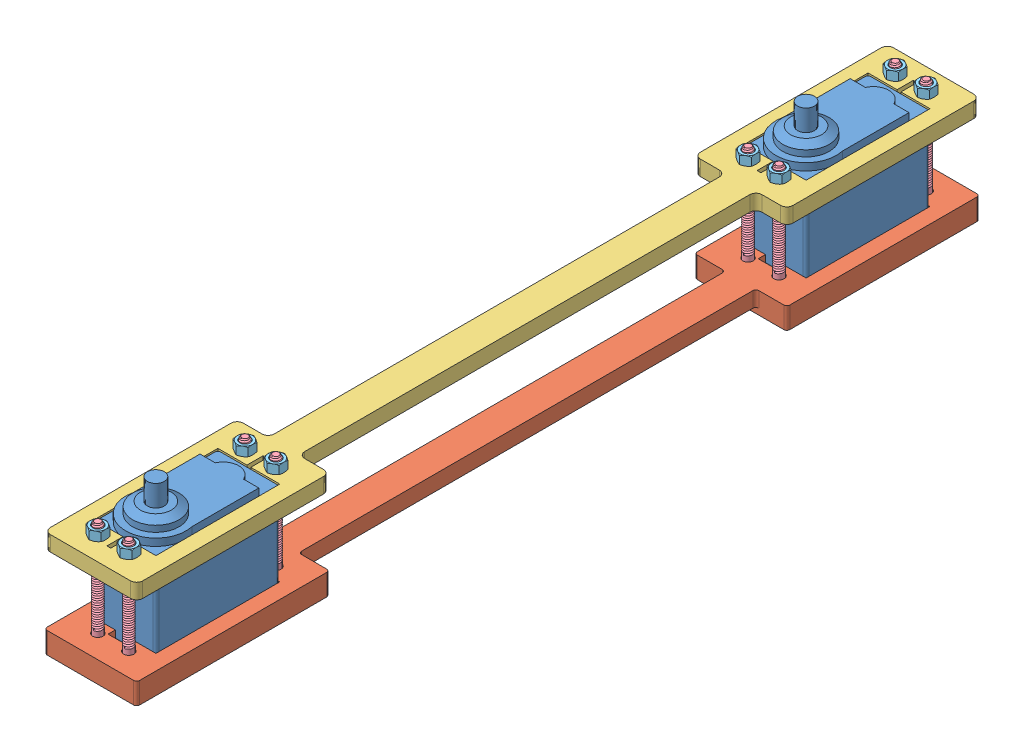
SolidWorks assembly Assem4, configuration Default. Lengths in mm.
Overall size (30.32 57.1 276.6).
20 component instances, 5 part files, 49 mates.
Components (placement in the parent):
- Motor3-1: Motor3 [Default] at origin size (20.32 45.1 53.29)
- Motor3-2: Motor3 [Default] at (0 0 -213.3) size (20.32 45.1 53.29)
- Part3-1: Part3 [Default] at (0 -35.6 -223.4854) x (0 -1 0) z (0 0 -1) size (17 30.32 276.6)
- Part4-1: Part4 [Default] at (0 -12.82 -10.1854) x (0 1 0) z (0 0 1) size (5 30.32 276.6)
- straf3_dolg37-1: straf3_dolg37 [Default] at (5.08 -40.74 13.9446) x (1 0 0) z (0 0 -1) size (7.72 39.83 7.72)
- straf3_dolg37-2: straf3_dolg37 [Default] at (-5.08 -40.74 13.9446) x (1 0 0) z (0 0 -1) size (7.72 39.83 7.72)
- straf3_dolg37-3: straf3_dolg37 [Default] at (-5.08 -40.74 -34.3154) x (1 0 0) z (0 0 -1) size (7.72 39.83 7.72)
- straf3_dolg37-4: straf3_dolg37 [Default] at (5.08 -40.74 -34.3154) x (1 0 0) z (0 0 -1) size (7.72 39.83 7.72)
- straf3_dolg37-6: straf3_dolg37 [Default] at (5.08 -40.74 -199.3554) x (1 0 0) z (0 0 -1) size (7.72 39.83 7.72)
- straf3_dolg37-5: straf3_dolg37 [Default] at (-5.08 -40.74 -199.3554) x (1 0 0) z (0 0 -1) size (7.72 39.83 7.72)
- straf3_dolg37-7: straf3_dolg37 [Default] at (-5.08 -40.74 -247.6154) x (1 0 0) z (0 0 -1) size (7.72 39.83 7.72)
- straf3_dolg37-8: straf3_dolg37 [Default] at (5.08 -40.74 -247.6154) x (0 0 1) z (1 0 0) size (7.72 39.83 7.72)
- navrtka2-1: navrtka2 [Default] at (-5.08 -6.32 13.9446) x (0.998982 0 -0.0451) z (0 -1 0) size (5.57 5.77 3)
- navrtka2-2: navrtka2 [Default] at (5.08 -6.32 13.9446) x (0.998982 0 -0.0451) z (0 -1 0) size (5.57 5.77 3)
- navrtka2-3: navrtka2 [Default] at (-5.08 -6.32 -34.3154) x (0.998982 0 -0.0451) z (0 -1 0) size (5.57 5.77 3)
- navrtka2-4: navrtka2 [Default] at (5.08 -6.32 -34.3154) x (0.998982 0 -0.0451) z (0 -1 0) size (5.57 5.77 3)
- navrtka2-5: navrtka2 [Default] at (-5.08 -6.32 -199.3554) x (0.998982 0 -0.0451) z (0 -1 0) size (5.57 5.77 3)
- navrtka2-6: navrtka2 [Default] at (-5.08 -6.32 -247.6154) x (0.998982 0 -0.0451) z (0 -1 0) size (5.57 5.77 3)
- navrtka2-7: navrtka2 [Default] at (5.08 -6.32 -247.6154) x (0.998982 0 -0.0451) z (0 -1 0) size (5.57 5.77 3)
- navrtka2-8: navrtka2 [Default] at (5.08 -6.32 -199.3554) x (0.998982 0 -0.0451) z (0 -1 0) size (5.57 5.77 3)
Mates (geometry in assembly coordinates):
- Concentric1: concentric aligned: cylinder of Motor3-1 through (5.08 -12.82 13.9446) axis (0 -1 0) radius 1.5; cylinder of Part4-1 through (5.08 -7.82 13.9446) axis (0 -1 0) radius 1.5
- Concentric2: concentric aligned: cylinder of Motor3-1 through (-5.08 -12.82 -34.3154) axis (0 -1 0) radius 1.5; cylinder of Part4-1 through (-5.08 -7.82 -34.3154) axis (0 -1 0) radius 1.5
- Coincident7: coincident anti-aligned: plane of Motor3-1 through (0 -12.82 -20.3454) normal (0 1 0); plane of Part4-1 through (0 -12.82 -10.1854) normal (0 -1 0)
- Concentric3: concentric aligned: cylinder of Part3-1 through (5.08 -42.6 13.9446) axis (0 -1 0) radius 1.7; cylinder of Part4-1 through (5.08 -7.82 13.9446) axis (0 -1 0) radius 1.5
- Concentric4: concentric aligned: cylinder of Part3-1 through (-5.08 -42.6 -247.6154) axis (0 -1 0) radius 1.7; cylinder of Part4-1 through (-5.08 -7.82 -247.6154) axis (0 -1 0) radius 1.5
- Concentric5: concentric aligned: cylinder of Motor3-2 through (-5.08 -12.82 -247.6154) axis (0 -1 0) radius 1.5; cylinder of Part4-1 through (-5.08 -7.82 -247.6154) axis (0 -1 0) radius 1.5
- Concentric6: concentric aligned: cylinder of Motor3-2 through (5.08 -12.82 -199.3554) axis (0 -1 0) radius 1.5; cylinder of Part4-1 through (5.08 -7.82 -199.3554) axis (0 -1 0) radius 1.5
- Coincident8: coincident anti-aligned: plane of Motor3-2 through (0 -12.82 -233.6454) normal (0 1 0); plane of Part4-1 through (0 -12.82 -10.1854) normal (0 -1 0)
- Coincident9: coincident anti-aligned: plane of Motor3-2 through (0 -40.6 -233.6454) normal (0 -1 0); plane of Part3-1 through (0 -40.6 -223.4854) normal (0 1 0)
- Coincident10: coincident aligned: cone of Part3-1 through (5.08 -42.6 -247.6154) axis (0 1 0); cone of straf3_dolg37-8 through (5.08 -40.74 -247.6154) axis (0 1 0)
- Coincident11: coincident aligned: cone of Part3-1 through (-5.08 -42.6 -247.6154) axis (0 1 0); cone of straf3_dolg37-7 through (-5.08 -40.74 -247.6154) axis (0 1 0)
- Coincident12: coincident aligned: cone of Part3-1 through (5.08 -42.6 -199.3554) axis (0 1 0); cone of straf3_dolg37-6 through (5.08 -40.74 -199.3554) axis (0 1 0)
- Coincident13: coincident aligned: cone of Part3-1 through (-5.08 -42.6 -199.3554) axis (0 1 0); cone of straf3_dolg37-5 through (-5.08 -40.74 -199.3554) axis (0 1 0)
- Coincident14: coincident aligned: cone of Part3-1 through (5.08 -42.6 -34.3154) axis (0 1 0); cone of straf3_dolg37-4 through (5.08 -40.74 -34.3154) axis (0 1 0)
- Coincident15: coincident aligned: cone of Part3-1 through (-5.08 -42.6 -34.3154) axis (0 1 0); cone of straf3_dolg37-3 through (-5.08 -40.74 -34.3154) axis (0 1 0)
- Coincident16: coincident aligned: cone of Part3-1 through (5.08 -42.6 13.9446) axis (0 1 0); cone of straf3_dolg37-1 through (5.08 -40.74 13.9446) axis (0 1 0)
- Coincident17: coincident aligned: cone of Part3-1 through (-5.08 -42.6 13.9446) axis (0 1 0); cone of straf3_dolg37-2 through (-5.08 -40.74 13.9446) axis (0 1 0)
- Concentric15: concentric anti-aligned: cylinder of Part4-1 through (5.08 -7.82 -247.6154) axis (0 -1 0) radius 1.5; circle of navrtka2-7
- Coincident18: coincident anti-aligned: plane of Part4-1 through (0 -7.82 -10.1854) normal (0 1 0); plane of navrtka2-7 through (5.08 -7.82 -247.6154) normal (0 -1 0)
- Concentric16: concentric anti-aligned: cylinder of Part4-1 through (-5.08 -7.82 -247.6154) axis (0 -1 0) radius 1.5; circle of navrtka2-6
- Coincident19: coincident anti-aligned: plane of Part4-1 through (0 -7.82 -10.1854) normal (0 1 0); plane of navrtka2-6 through (-5.08 -7.82 -247.6154) normal (0 -1 0)
- Concentric17: concentric anti-aligned: cylinder of Part4-1 through (5.08 -7.82 -199.3554) axis (0 -1 0) radius 1.5; circle of navrtka2-8
- Coincident20: coincident anti-aligned: plane of Part4-1 through (0 -7.82 -10.1854) normal (0 1 0); plane of navrtka2-8 through (5.08 -7.82 -199.3554) normal (0 -1 0)
- Concentric18: concentric anti-aligned: cylinder of Part4-1 through (-5.08 -7.82 -199.3554) axis (0 -1 0) radius 1.5; circle of navrtka2-5
- Coincident21: coincident anti-aligned: plane of Part4-1 through (0 -7.82 -10.1854) normal (0 1 0); plane of navrtka2-5 through (-5.08 -7.82 -199.3554) normal (0 -1 0)
- Concentric19: concentric anti-aligned: cylinder of Part4-1 through (5.08 -7.82 -34.3154) axis (0 -1 0) radius 1.5; circle of navrtka2-4
- Coincident22: coincident anti-aligned: plane of Part4-1 through (0 -7.82 -10.1854) normal (0 1 0); plane of navrtka2-4 through (5.08 -7.82 -34.3154) normal (0 -1 0)
- Concentric20: concentric anti-aligned: cylinder of Part4-1 through (-5.08 -7.82 -34.3154) axis (0 -1 0) radius 1.5; circle of navrtka2-3
- Coincident23: coincident anti-aligned: plane of Part4-1 through (0 -7.82 -10.1854) normal (0 1 0); plane of navrtka2-3 through (-5.08 -7.82 -34.3154) normal (0 -1 0)
- Concentric21: concentric anti-aligned: cylinder of Part4-1 through (5.08 -7.82 13.9446) axis (0 -1 0) radius 1.5; circle of navrtka2-2
- Coincident24: coincident anti-aligned: plane of Part4-1 through (0 -7.82 -10.1854) normal (0 1 0); plane of navrtka2-2 through (5.08 -7.82 13.9446) normal (0 -1 0)
- Concentric22: concentric anti-aligned: cylinder of Part4-1 through (-5.08 -7.82 13.9446) axis (0 -1 0) radius 1.5; circle of navrtka2-1
- Coincident25: coincident anti-aligned: plane of Part4-1 through (0 -7.82 -10.1854) normal (0 1 0); plane of navrtka2-1 through (-5.08 -7.82 13.9446) normal (0 -1 0)
- Parallel1: parallel aligned: plane of Part4-1 through (15.16 -7.82 -10.1854) normal (1 0 0); plane of navrtka2-2 through (7.58 -4.82 12.5012) normal (1 0 0)
- Parallel2: parallel aligned: plane of Part4-1 through (15.16 -7.82 -10.1854) normal (1 0 0); plane of navrtka2-1 through (-2.58 -4.82 12.5012) normal (1 0 0)
- Parallel3: parallel aligned: plane of Part4-1 through (15.16 -7.82 -10.1854) normal (1 0 0); plane of navrtka2-3 through (-2.58 -4.82 -35.7588) normal (1 0 0)
- Parallel4: parallel aligned: plane of Part4-1 through (15.16 -7.82 -10.1854) normal (1 0 0); plane of navrtka2-4 through (7.58 -4.82 -35.7588) normal (1 0 0)
- Parallel5: parallel aligned: plane of Part4-1 through (15.16 -7.82 -10.1854) normal (1 0 0); plane of navrtka2-8 through (7.58 -4.82 -200.7988) normal (1 0 0)
- Parallel6: parallel aligned: plane of Part4-1 through (15.16 -7.82 -10.1854) normal (1 0 0); plane of navrtka2-5 through (-2.58 -4.82 -200.7988) normal (1 0 0)
- Parallel7: parallel aligned: plane of Part4-1 through (15.16 -7.82 -10.1854) normal (1 0 0); plane of navrtka2-6 through (-2.58 -4.82 -249.0588) normal (1 0 0)
- Parallel8: parallel aligned: plane of Part4-1 through (15.16 -7.82 -10.1854) normal (1 0 0); plane of navrtka2-7 through (7.58 -4.82 -249.0588) normal (1 0 0)
- Parallel11: parallel aligned: line of Part3-1 through (15.16 -42.6 -254.1354) axis (0 0 1); line of straf3_dolg37-8 through (4.905 -43.24 -250.6154) axis (0 0 1)
- Parallel12: parallel anti-aligned: line of Part3-1 through (15.16 -42.6 -254.1354) axis (0 0 1); line of straf3_dolg37-7 through (-5.255 -43.24 -247.7904) axis (0 0 -1)
- Parallel13: parallel anti-aligned: line of Part3-1 through (15.16 -42.6 -254.1354) axis (0 0 1); line of straf3_dolg37-6 through (4.905 -43.24 -199.5304) axis (0 0 -1)
- Parallel14: parallel anti-aligned: line of Part3-1 through (15.16 -42.6 -254.1354) axis (0 0 1); line of straf3_dolg37-5 through (-5.255 -43.24 -199.5304) axis (0 0 -1)
- Parallel15: parallel anti-aligned: line of Part3-1 through (15.16 -42.6 -40.8354) axis (0 0 1); line of straf3_dolg37-4 through (4.905 -43.24 -34.4904) axis (0 0 -1)
- Parallel16: parallel anti-aligned: line of Part3-1 through (15.16 -42.6 -40.8354) axis (0 0 1); line of straf3_dolg37-3 through (-5.255 -43.24 -34.4904) axis (0 0 -1)
- Parallel17: parallel anti-aligned: line of Part3-1 through (15.16 -42.6 -40.8354) axis (0 0 1); line of straf3_dolg37-1 through (4.905 -43.24 13.7696) axis (0 0 -1)
- Parallel18: parallel anti-aligned: line of Part3-1 through (15.16 -42.6 -40.8354) axis (0 0 1); line of straf3_dolg37-2 through (-5.255 -43.24 13.7696) axis (0 0 -1)
